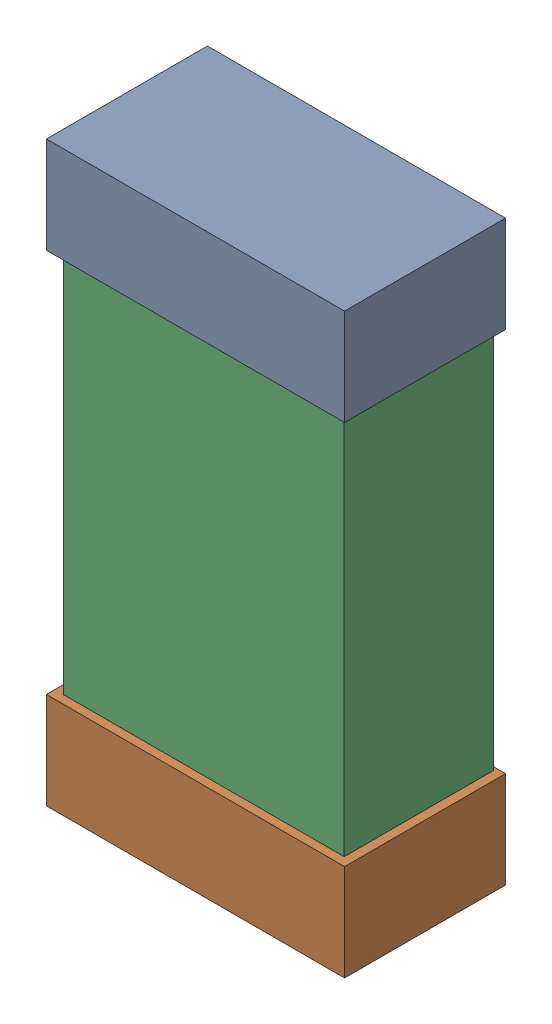
SolidWorks assembly C38, configuration Default. Lengths in mm.
Overall size (0.85 1.65 0.46).
6 component instances, 2 part files, 0 mates.
Components (placement in the parent):
- 432138512_46-1: 432138512_46 [Default] at (17.3802 50.8362 -0.8715) size (0.85 0.28 0.46)
  - Extruded-1: Extruded [Default] at origin size (0.85 0.28 0.46)
- 432138512_47-1: 432138512_47 [Default] at (17.3802 49.4647 -0.8715) size (0.85 0.28 0.46)
  - Extruded-1: Extruded [Default] at origin size (0.85 0.28 0.46)
- 432124816_23-1: 432124816_23 [Default] at (17.3802 50.1505 -0.8615) size (0.8 1.5 0.42)
  - Extruded (1)-1: Extruded (1) [Default] at origin size (0.8 1.5 0.42)
